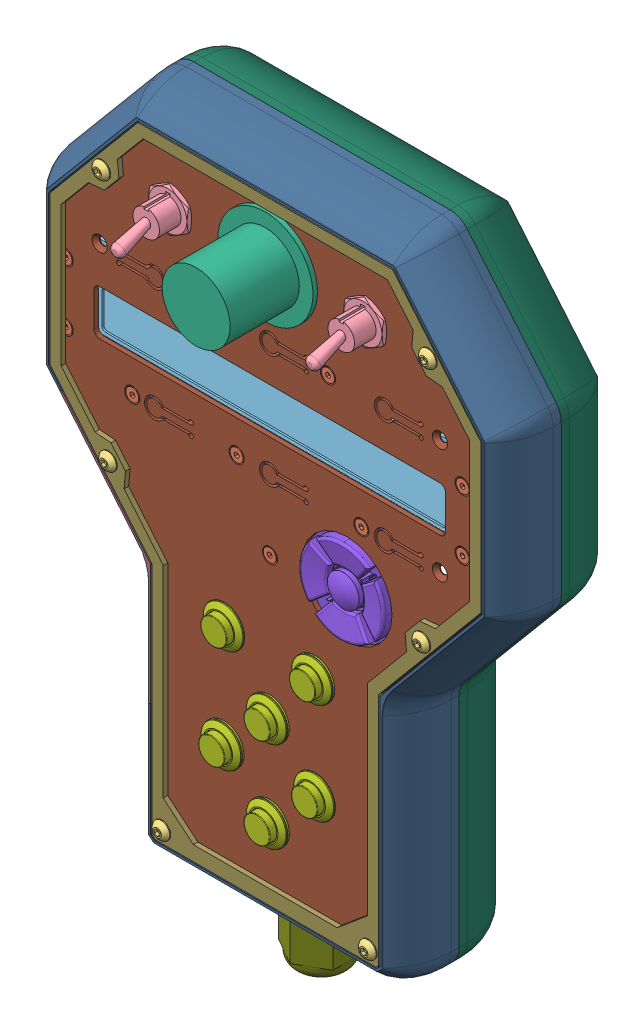
SolidWorks assembly Montagem, configuration Rounded. Lengths in mm.
Overall size (211 315 80.5).
60 component instances, 19 part files, 130 mates.
Components (placement in the parent):
- hex nut style 1 gradeab_din-3: hex nut style 1 gradeab_din [Hexagon Nut ISO 4032 - M4 - W - N] at (-95.2029 -0.5297 -15.05) x (-0.766044 -0.642788 0) z (0 0 1)
- hex nut style 1 gradeab_din-4: hex nut style 1 gradeab_din [Hexagon Nut ISO 4032 - M4 - W - N] at (42.9071 -0.5197 -15.05) x (0.766044 -0.642788 0) z (0 0 1)
- hex nut style 1 gradeab_din-5: hex nut style 1 gradeab_din [Hexagon Nut ISO 4032 - M4 - W - N] at (-69.6429 -49.9305 2.95) x (0.5 0.866025 0) z (0 0 1)
- hex nut style 1 gradeab_din-6: hex nut style 1 gradeab_din [Hexagon Nut ISO 4032 - M4 - W - N] at (33.6932 120.5695 2.95) x (0.766044 0.642788 0) z (0 0 1)
- hex nut style 1 gradeab_din-7: hex nut style 1 gradeab_din [Hexagon Nut ISO 4032 - M4 - W - N] at (17.3571 -99.7712 2.95)
- hex nut style 1 gradeab_din-8: hex nut style 1 gradeab_din [Hexagon Nut ISO 4032 - M4 - W - N] at (-85.979 120.5695 2.95) x (0.766044 -0.642788 0) z (0 0 1)
- hex nut style 1 gradeab_din-9: hex nut style 1 gradeab_din [Hexagon Nut ISO 4032 - M4 - W - N] at (-69.6429 -99.7712 2.95)
- hex nut style 1 gradeab_din-10: hex nut style 1 gradeab_din [Hexagon Nut ISO 4032 - M4 - W - N] at (45.8324 109.2141 -7.45) x (0.939693 -0.34202 0) z (0 0 -1)
- hex nut style 1 gradeab_din-11: hex nut style 1 gradeab_din [Hexagon Nut ISO 4032 - M4 - W - N] at (-71.6429 -129.7045 -7.45) x (0.5 0.866025 0) z (0 0 -1)
- hex nut style 1 gradeab_din-12: hex nut style 1 gradeab_din [Hexagon Nut ISO 4032 - M4 - W - N] at (19.3571 -129.7045 -7.45) x (1 0 0) z (0 0 -1)
- hex nut style 1 gradeab_din-13: hex nut style 1 gradeab_din [Hexagon Nut ISO 4032 - M4 - W - N] at (-98.1182 109.2141 -7.45) x (-0.939693 -0.34202 0) z (0 0 -1)
- socket countersunk head screw_din-8: socket countersunk head screw_din [DIN 7991 - M3 x 16 --- 12.8C] at (58.8311 39.2309 11.75) x (0 0 -1) z (1 0 0)
- socket countersunk head screw_din-9: socket countersunk head screw_din [DIN 7991 - M3 x 16 --- 12.8C] at (-86.7826 27.8805 11.75) x (0 0 -1) z (-0.923728 -0.383049 0)
- socket countersunk head screw_din-10: socket countersunk head screw_din [DIN 7991 - M3 x 16 --- 12.8C] at (-116.1689 65.7309 11.75) x (0 0 -1) z (-0.923728 -0.383049 0)
- socket countersunk head screw_din-11: socket countersunk head screw_din [DIN 7991 - M3 x 16 --- 12.8C] at (-0.483 78.4595 11.75) x (0 0 -1) z (0.923728 0.383049 0)
- socket countersunk head screw_din-12: socket countersunk head screw_din [DIN 7991 - M3 x 16 --- 12.8C] at (-116.1689 39.2309 11.75) x (0 0 -1) z (-0.923728 -0.383049 0)
- socket countersunk head screw_din-13: socket countersunk head screw_din [DIN 7991 - M3 x 16 --- 12.8C] at (-52.483 78.4595 11.75) x (0 0 -1) z (0.923728 0.383049 0)
- socket countersunk head screw_din-14: socket countersunk head screw_din [DIN 7991 - M3 x 16 --- 12.8C] at (58.8311 65.7309 11.75) x (0 0 -1) z (0.923728 0.383049 0)
- socket countersunk head screw_din-15: socket countersunk head screw_din [DIN 7991 - M3 x 16 --- 12.8C] at (14.2174 27.8805 11.75) x (0 0 -1) z (1 0 0)
- socket countersunk head screw_din-16: socket countersunk head screw_din [DIN 7991 - M3 x 16 --- 12.8C] at (-40.7826 27.8805 11.75) x (0 0 -1) z (0.277326 0.960776 0)
- socket countersunk head screw_din-17: socket countersunk head screw_din [DIN 7991 - M3 x 16 --- 12.8C] at (-26.2001 -3.0051 11.75) x (0 0 -1) z (-0.006263 -0.99998 0)
- hex nut style 1 gradeab_din-15: hex nut style 1 gradeab_din [Hexagon Nut ISO 4032 - M3 - W - N] at (-40.7826 27.8805 0.1586) x (0.012479 -0.999922 0) z (0 0 -1)
- hex nut style 1 gradeab_din-16: hex nut style 1 gradeab_din [Hexagon Nut ISO 4032 - M3 - W - N] at (-52.483 78.4595 0.1586) x (0.904381 -0.426726 0) z (0 0 -1)
- hex nut style 1 gradeab_din-17: hex nut style 1 gradeab_din [Hexagon Nut ISO 4032 - M3 - W - N] at (-0.483 78.4595 0.1586) x (-0.993944 0.109886 0) z (0 0 -1)
- hex nut style 1 gradeab_din-18: hex nut style 1 gradeab_din [Hexagon Nut ISO 4032 - M3 - W - N] at (14.2174 27.8805 0.1586) x (-0.816279 -0.577658 0) z (0 0 -1)
- hex nut style 1 gradeab_din-19: hex nut style 1 gradeab_din [Hexagon Nut ISO 4032 - M3 - W - N] at (-86.7826 27.8805 0.1586) x (-0.525463 -0.850817 0) z (0 0 -1)
- hex nut style 1 gradeab_din-20: hex nut style 1 gradeab_din [Hexagon Nut ISO 4032 - M3 - W - N] at (-116.1689 65.7309 -3.318) x (0.297598 -0.954691 0) z (0 0 -1)
- hex nut style 1 gradeab_din-21: hex nut style 1 gradeab_din [Hexagon Nut ISO 4032 - M3 - W - N] at (-116.1689 39.2309 -3.318) x (0.646896 0.762578 0) z (0 0 -1)
- hex nut style 1 gradeab_din-22: hex nut style 1 gradeab_din [Hexagon Nut ISO 4032 - M3 - W - N] at (58.8311 65.7309 -3.318) x (0.923728 0.383049 0) z (0 0 -1)
- hex nut style 1 gradeab_din-23: hex nut style 1 gradeab_din [Hexagon Nut ISO 4032 - M3 - W - N] at (58.8311 39.2309 -3.318) x (0.923728 0.383049 0) z (0 0 -1)
- hex nut style 1 gradeab_din-24: hex nut style 1 gradeab_din [Hexagon Nut ISO 4032 - M3 - W - N] at (-26.2001 -3.0051 0.1586) x (0.05846 -0.99829 0) z (0 0 -1)
- socket button head screw_iso-9: socket button head screw_iso [ISO 7380 - M4 x 16 --- 16N] at (45.8295 109.2085 15.95) x (0 0 -1) z (1 0 0)
- socket button head screw_iso-10: socket button head screw_iso [ISO 7380 - M4 x 16 --- 16N] at (-98.1153 109.2085 15.95) x (0 0 -1) z (0.767389 -0.641182 0)
- socket button head screw_iso-11: socket button head screw_iso [ISO 7380 - M4 x 16 --- 16N] at (-71.6429 -129.7005 15.95) x (0 0 -1) z (1 0 0)
- socket button head screw_iso-12: socket button head screw_iso [ISO 7380 - M4 x 16 --- 16N] at (19.3571 -129.7005 15.95) x (0 0 -1) z (1 0 0)
- socket button head screw_iso-14: socket button head screw_iso [ISO 7380 - M4 x 16 --- 16N] at (-95.1957 -0.5218 15.95) x (0 0 -1) z (1 0 0)
- socket button head screw_iso-13: socket button head screw_iso [ISO 7380 - M4 x 16 --- 16N] at (42.9099 -0.5218 15.95) x (0 0 -1) z (1 0 0)
- BCV3 112 103 - Controle chave geral-1: BCV3 112 103 - Controle chave geral [Default] at (-69.1429 108.0695 2.25)
- BCV3 112 103 - Controle chave geral-2: BCV3 112 103 - Controle chave geral [Default] at (16.8571 108.0695 2.25)
- LCD Display 4002-1: LCD Display 4002 [Valor predeterminado] at (-28.6689 52.4809 -3.8644)
- Botão emergencia-1: Botão emergencia [Valor predeterminado] at (-26.1429 108.0695 -28.25) x (0.351629 -0.93614 0) z (-0.93614 -0.351629 0)
- AV16HA-1: AV16HA [Valor predeterminado] at (-26.1429 -104.9305 -2.3) x (-0.899754 -0.436397 0) z (-0.436397 0.899754 0)
- AV16HA-2: AV16HA [Valor predeterminado] at (-46.1429 -39.9305 -3.25) x (0.225316 -0.974286 0) z (-0.974286 -0.225316 0)
- AV16HA-3: AV16HA [Valor predeterminado] at (-26.1429 -64.9305 -2.3) x (0.278036 0.960571 0) z (0.960571 -0.278036 0)
- AV16HA-4: AV16HA [Valor predeterminado] at (-6.1429 -84.9305 -3.25) x (0.980248 0.197772 0) z (0.197772 -0.980248 0)
- AV16HA-5: AV16HA [Valor predeterminado] at (-46.1429 -84.9305 -2.3) x (0.999797 0.02015 0) z (0.02015 -0.999797 0)
- AV16HA-6: AV16HA [Valor predeterminado] at (-6.1429 -39.9305 -2.3) x (-0.950101 -0.311942 0) z (-0.311942 0.950101 0)
- PCB-2: PCB [Valor predeterminado] at (-91.4326 8.3805 4.15)
- Teclas_Superiores-2: Teclas_Superiores [Valor predeterminado] at (-91.433 46.0455 4.15)
- TEC001 - Moldura -1: TEC001 - Moldura  [Valor predeterminado] at (-26.1429 -144.6278 -11.25)
- TEC002 - Placa Superior-1: TEC002 - Placa Superior [Valor predeterminado] at (-25.2999 1.2599 9.75)
- TEC003 - Moldura alumínio-1: TEC003 - Moldura alumínio [Valor predeterminado] at (-26.4426 -0.0902 11.75)
- TEC004 - Moldura Borracha-1: TEC004 - Moldura Borracha [Valor predeterminado] at (-26.6429 -144.6278 -11.25)
- TEC005 - Moldura Borracha Inferior-1: TEC005 - Moldura Borracha Inferior [Valor predeterminado] at (-26.6429 -144.6278 -11.25)
- TEC006 - Placa Inferior-1: TEC006 - Placa Inferior [Valor predeterminado] at (-25.2999 1.2599 -34.75) (hidden)
- TEC007 - Moldura  Inferior-1: TEC007 - Moldura  Inferior [Valor predeterminado] at (-26.1429 -144.6278 -11.25)
- Prensa cabo-1: Prensa cabo [Valor predeterminado] at (-26.1429 -154.9305 -11.0191) x (0.5 0 0.866025) z (0 -1 0)
- TEC008 - Pino-1: TEC008 - Pino [Valor predeterminado] at (-127.6429 32.3003 0.75) x (0.794362 -0.607445 0) z (0.607445 0.794362 0)
- TEC008 - Pino-2: TEC008 - Pino [Valor predeterminado] at (-80.1429 -114.1997 -24.25) x (0.610836 -0.791757 0) z (-0.791757 -0.610836 0)
- placa inferior-1: placa inferior [Valor predeterminado] at (-18.5596 4.7575 -324.8091) x (-1 0 0) z (0 0 -1) (hidden)
Mates (geometry in assembly coordinates):
- Coincidente2: coincident: plane of TEC001 - Moldura -1 through (-26.1429 -144.6278 13.75) normal (0 0 1); plane of Botão emergencia-1 through (-33.5271 127.7285 13.75) normal (0 0 1)
- Coincidente24: coincident: plane of TEC001 - Moldura -1 through (-26.1429 -144.6278 9.75) normal (0 0 1); plane of TEC002 - Placa Superior-1 through (-25.2999 1.2599 9.75) normal (0 0 -1)
- Coincidente35: coincident: plane of TEC001 - Moldura -1 through (-49.8107 -84.1997 -11.25) normal (0 1 0); plane of TEC004 - Moldura Borracha-1 through (-50.3107 -84.1997 -11.25) normal (0 -1 0)
- Coincidente36: coincident: plane of TEC002 - Placa Superior-1 through (-25.2999 1.2599 9.75) normal (0 0 -1); plane of TEC004 - Moldura Borracha-1 through (-26.6429 -144.6278 9.75) normal (0 0 1)
- Concêntrico6: concentric: cylinder of AV16HA-1 through (-26.1429 -104.9305 -2.3) axis (0 0 1) radius 7.95; cylinder of TEC002 - Placa Superior-1 through (-26.1429 -104.9305 9.749) axis (0 0 1) radius 8
- Tangente1: tangent: plane of TEC002 - Placa Superior-1 through (-25.2999 1.2599 11.75) normal (0 0 1); face of AV16HA-1
- Concêntrico9: concentric: cylinder of AV16HA-4 through (-6.1429 -84.9305 -3.25) axis (0 0 1) radius 7.95; cylinder of TEC002 - Placa Superior-1 through (-6.1429 -84.9305 9.749) axis (0 0 1) radius 8
- Concêntrico10: concentric: cylinder of AV16HA-3 through (-26.1429 -64.9305 -2.3) axis (0 0 1) radius 7.95; cylinder of TEC002 - Placa Superior-1 through (-26.1429 -64.9305 9.749) axis (0 0 1) radius 8
- Tangente2: tangent: plane of TEC002 - Placa Superior-1 through (-25.2999 1.2599 11.75) normal (0 0 1); face of AV16HA-5
- Tangente3: tangent: plane of TEC002 - Placa Superior-1 through (-25.2999 1.2599 11.75) normal (0 0 1); face of AV16HA-6
- Tangente4: tangent: plane of TEC002 - Placa Superior-1 through (-25.2999 1.2599 11.75) normal (0 0 1); face of AV16HA-4
- Tangente5: tangent: plane of TEC002 - Placa Superior-1 through (-25.2999 1.2599 11.75) normal (0 0 1); face of AV16HA-2
- Tangente6: tangent: plane of TEC002 - Placa Superior-1 through (-25.2999 1.2599 11.75) normal (0 0 1); face of AV16HA-3
- Concêntrico12: concentric: cylinder of Botão emergencia-1 through (-26.1429 108.0695 -50.7451) axis (0 0 -1) radius 15; cylinder of TEC002 - Placa Superior-1 through (-26.1429 108.0695 9.749) axis (0 0 1) radius 11.25
- Concêntrico13: concentric: cylinder of BCV3 112 103 - Controle chave geral-1 through (-69.1429 108.0695 23.25) axis (0 0 -1) radius 5.85; cylinder of TEC002 - Placa Superior-1 through (-69.1429 108.0695 9.749) axis (0 0 1) radius 6
- Concêntrico15: concentric: cylinder of BCV3 112 103 - Controle chave geral-2 through (16.8571 108.0695 23.25) axis (0 0 -1) radius 5.85; cylinder of TEC002 - Placa Superior-1 through (16.8571 108.0695 9.749) axis (0 0 1) radius 6
- Coincidente38: coincident: plane of BCV3 112 103 - Controle chave geral-1 through (-69.1429 117.8845 11.75) normal (0 0 -1); plane of TEC002 - Placa Superior-1 through (-25.2999 1.2599 11.75) normal (0 0 1)
- Coincidente39: coincident: plane of BCV3 112 103 - Controle chave geral-2 through (16.8571 117.8845 11.75) normal (0 0 -1); plane of TEC002 - Placa Superior-1 through (-25.2999 1.2599 11.75) normal (0 0 1)
- Coincidente40: coincident: plane of TEC001 - Moldura -1 through (-39.9429 -142.4305 -3.2826) normal (0.5 0 -0.866025); plane of Prensa cabo-1 through (-39.7429 -142.4305 -3.1671) normal (-0.5 0 0.866025)
- Coincidente41: coincident: plane of TEC001 - Moldura -1 through (-26.1429 -142.4305 4.6849) normal (-0.5 0 -0.866025); plane of Prensa cabo-1 through (-26.1429 -142.4305 4.6849) normal (0.5 0 0.866025)
- Coincidente42: coincident: plane of TEC001 - Moldura -1 through (-26.1429 -142.4305 -11.25) normal (0 1 0); plane of Prensa cabo-1 through (-26.1429 -142.4305 -11.0191) normal (0 -1 0)
- Distância9: distance = 0.5 mm: plane of TEC002 - Placa Superior-1 through (-121.1429 88.7866 11.75) normal (-1 0 0); plane of TEC001 - Moldura -1 through (-121.6429 88.9571 9.75) normal (1 0 0)
- Distância10: distance = 0.5 mm: plane of TEC002 - Placa Superior-1 through (30.0211 135.0695 11.75) normal (0 1 0); plane of TEC001 - Moldura -1 through (30.2446 135.5695 9.75) normal (0 -1 0)
- Coincidente49: coincident: plane of TEC002 - Placa Superior-1 through (-25.2999 1.2599 11.75) normal (0 0 1); plane of TEC003 - Moldura alumínio-1 through (-26.4426 -0.0902 11.75) normal (0 0 -1)
- Coincidente50: coincident: plane of TEC002 - Placa Superior-1 through (-121.1429 88.7866 11.75) normal (-1 0 0); plane of TEC003 - Moldura alumínio-1 through (-121.1429 88.7866 13.75) normal (-1 0 0)
- Coincidente51: coincident: plane of TEC002 - Placa Superior-1 through (-74.8228 -134.9305 11.75) normal (0 -1 0); plane of TEC003 - Moldura alumínio-1 through (-74.8228 -134.9305 13.75) normal (0 -1 0)
- Coincidente52: coincident: plane of TEC001 - Moldura -1 through (-86.6429 -144.6278 13.75) normal (-1 0 0); plane of TEC004 - Moldura Borracha-1 through (-86.6429 -144.6278 13.75) normal (-1 0 0)
- Coincidente53: coincident: plane of TEC001 - Moldura -1 through (-26.1429 145.5695 13.75) normal (0 1 0); plane of TEC007 - Moldura  Inferior-1 through (-26.1429 145.5695 13.75) normal (0 1 0)
- Coincidente54: coincident: plane of TEC001 - Moldura -1 through (-204.8631 5.3363 13.75) normal (-0.766044 0.642788 0); plane of TEC007 - Moldura  Inferior-1 through (-204.8631 5.3363 13.75) normal (-0.766044 0.642788 0)
- Coincidente55: coincident: plane of TEC001 - Moldura -1 through (152.5774 5.3363 13.75) normal (0.766044 0.642788 0); plane of TEC007 - Moldura  Inferior-1 through (152.5774 5.3363 13.75) normal (0.766044 0.642788 0)
- Coincidente56: coincident: plane of TEC006 - Placa Inferior-1 through (-25.2999 1.2599 -33.25) normal (0 0 1); plane of TEC007 - Moldura  Inferior-1 through (-26.1429 -144.6278 -33.25) normal (0 0 -1)
- Distância11: distance = 0.5 mm: plane of TEC006 - Placa Inferior-1 through (30.0211 135.0695 -33.25) normal (0 1 0); plane of TEC007 - Moldura  Inferior-1 through (30.2446 135.5695 -33.25) normal (0 -1 0)
- Distância12: distance = 0.5 mm: plane of TEC006 - Placa Inferior-1 through (-121.1429 88.7866 -33.25) normal (-1 0 0); plane of TEC007 - Moldura  Inferior-1 through (-121.6429 88.9571 -33.25) normal (1 0 0)
- Coincidente57: coincident: plane of TEC007 - Moldura  Inferior-1 through (-26.1429 -144.6278 -11.25) normal (0 0 1); plane of TEC005 - Moldura Borracha Inferior-1 through (-26.6429 -144.6278 -11.25) normal (0 0 1)
- Coincidente58: coincident: plane of TEC007 - Moldura  Inferior-1 through (-49.8107 -84.1997 -11.25) normal (0 1 0); plane of TEC005 - Moldura Borracha Inferior-1 through (-50.3107 -84.1997 -11.25) normal (0 -1 0)
- Coincidente59: coincident: plane of TEC007 - Moldura  Inferior-1 through (-7.3536 -128.8618 13.75) normal (-0.766044 -0.642788 0); plane of TEC005 - Moldura Borracha Inferior-1 through (-7.5602 -128.6156 13.75) normal (-0.766044 -0.642788 0)
- Paralelo2: parallel: plane of TEC001 - Moldura -1 through (30.2446 135.5695 9.75) normal (0 -1 0); plane of BCV3 112 103 - Controle chave geral-1 through (-77.1429 122.5695 10.25) normal (0 1 0)
- Paralelo3: parallel: plane of TEC001 - Moldura -1 through (30.2446 135.5695 9.75) normal (0 -1 0); plane of BCV3 112 103 - Controle chave geral-2 through (8.8571 122.5695 10.25) normal (0 1 0)
- Concêntrico17: concentric: cylinder of TEC001 - Moldura -1 through (33.6932 120.5695 -11.25) axis (0 0 1) radius 2.2; cylinder of hex nut style 1 gradeab_din-6 through (33.6932 120.5695 -0.25) axis (0 0 1) radius 1.65
- Concêntrico18: concentric: cylinder of TEC001 - Moldura -1 through (-85.979 120.5695 -11.25) axis (0 0 1) radius 2.2; cylinder of hex nut style 1 gradeab_din-8 through (-85.979 120.5695 -0.25) axis (0 0 1) radius 1.65
- Paralelo4: parallel: plane of TEC001 - Moldura -1 through (-90.1865 121.3114 -0.25) normal (0.939693 0.34202 0); plane of hex nut style 1 gradeab_din-8 through (-89.9591 121.2713 -0.25) normal (-0.939693 -0.34202 0)
- Paralelo5: parallel: plane of TEC001 - Moldura -1 through (-87.4403 124.5843 -0.25) normal (0.766044 -0.642788 0); plane of hex nut style 1 gradeab_din-8 through (-87.3613 124.3672 -0.25) normal (-0.766044 0.642788 0)
- Coincidente67: coincident: plane of TEC001 - Moldura -1 through (-26.1429 -144.6278 -0.25) normal (0 0 1); plane of hex nut style 1 gradeab_din-8 through (-83.3812 123.6655 -0.25) normal (0 0 -1)
- Paralelo6: parallel: plane of TEC001 - Moldura -1 through (30.947 123.8424 -0.25) normal (0.939693 -0.34202 0); plane of hex nut style 1 gradeab_din-6 through (31.0955 123.6655 -0.25) normal (-0.939693 0.34202 0)
- Coincidente69: coincident: plane of TEC001 - Moldura -1 through (-26.1429 -144.6278 -0.25) normal (0 0 1); plane of hex nut style 1 gradeab_din-6 through (31.0955 123.6655 -0.25) normal (0 0 -1)
- Concêntrico21: concentric: cylinder of TEC004 - Moldura Borracha-1 through (-69.6429 -49.9305 -11.25) axis (0 0 1) radius 2.2; cylinder of hex nut style 1 gradeab_din-5 through (-69.6429 -49.9305 -0.25) axis (0 0 1) radius 1.65
- Paralelo9: parallel: plane of TEC004 - Moldura Borracha-1 through (-65.9429 -52.0667 -0.25) normal (-1 0 0); plane of hex nut style 1 gradeab_din-5 through (-73.1429 -47.9097 -0.25) normal (-1 0 0)
- Coincidente76: coincident: plane of TEC004 - Moldura Borracha-1 through (-26.6429 -144.6278 -0.25) normal (0 0 1); plane of hex nut style 1 gradeab_din-5 through (-73.1429 -47.9097 -0.25) normal (0 0 -1)
- Concêntrico22: concentric: cylinder of TEC001 - Moldura -1 through (17.3571 -99.7712 -11.25) axis (0 0 1) radius 2.2; cylinder of hex nut style 1 gradeab_din-7 through (17.3571 -99.7712 -0.25) axis (0 0 1) radius 1.65
- Paralelo10: parallel: plane of TEC001 - Moldura -1 through (21.0571 -101.9074 -0.25) normal (-1 0 0); plane of hex nut style 1 gradeab_din-7 through (13.8571 -97.7505 -0.25) normal (-1 0 0)
- Coincidente78: coincident: plane of TEC001 - Moldura -1 through (-26.1429 -144.6278 -0.25) normal (0 0 1); plane of hex nut style 1 gradeab_din-7 through (17.3571 -95.7298 -0.25) normal (0 0 -1)
- Concêntrico23: concentric: cylinder of TEC001 - Moldura -1 through (-69.6429 -99.7712 -11.25) axis (0 0 1) radius 2.2; cylinder of hex nut style 1 gradeab_din-9 through (-69.6429 -99.7712 -0.25) axis (0 0 1) radius 1.65
- Paralelo11: parallel: plane of TEC001 - Moldura -1 through (-65.9429 -101.9074 -0.25) normal (-1 0 0); plane of hex nut style 1 gradeab_din-9 through (-73.1429 -97.7505 -0.25) normal (-1 0 0)
- Coincidente80: coincident: plane of TEC001 - Moldura -1 through (-26.1429 -144.6278 -0.25) normal (0 0 1); plane of hex nut style 1 gradeab_din-9 through (-69.6429 -95.7298 -0.25) normal (0 0 -1)
- Concêntrico24: concentric: cylinder of TEC001 - Moldura -1 through (-71.6429 -129.7045 -11.25) axis (0 0 1) radius 2.2; cylinder of hex nut style 1 gradeab_din-11 through (-71.6429 -129.7045 -4.25) axis (0 0 -1) radius 1.65
- Paralelo12: parallel: plane of TEC001 - Moldura -1 through (-67.9429 -127.5683 3.75) normal (-0.5 -0.866025 0); plane of hex nut style 1 gradeab_din-11 through (-68.1429 -127.6838 -4.25) normal (0.5 0.866025 0)
- Concêntrico25: concentric: cylinder of TEC001 - Moldura -1 through (19.3571 -129.7045 -11.25) axis (0 0 1) radius 2.2; cylinder of hex nut style 1 gradeab_din-12 through (19.3571 -129.7045 -4.25) axis (0 0 -1) radius 1.65
- Paralelo13: parallel: plane of TEC001 - Moldura -1 through (15.6571 -131.8407 3.75) normal (1 0 0); plane of hex nut style 1 gradeab_din-12 through (22.8571 -131.7252 -4.25) normal (1 0 0)
- Concêntrico27: concentric: cylinder of TEC001 - Moldura -1 through (45.8324 109.2141 -11.25) axis (0 0 1) radius 2.2; cylinder of hex nut style 1 gradeab_din-10 through (45.8324 109.2141 -4.25) axis (0 0 -1) radius 1.65
- Paralelo14: parallel: plane of TEC001 - Moldura -1 through (43.0861 112.487 3.75) normal (0.173648 -0.984808 0); plane of hex nut style 1 gradeab_din-10 through (48.4302 106.1182 -4.25) normal (0.173648 -0.984808 0)
- Concêntrico28: concentric: cylinder of TEC001 - Moldura -1 through (-98.1182 109.2141 -11.25) axis (0 0 1) radius 2.2; cylinder of hex nut style 1 gradeab_din-13 through (-98.1182 109.2141 -4.25) axis (0 0 -1) radius 1.65
- Paralelo15: parallel: plane of TEC001 - Moldura -1 through (-99.5794 113.2289 3.75) normal (-0.173648 -0.984808 0); plane of hex nut style 1 gradeab_din-13 through (-96.7359 105.4164 -4.25) normal (-0.173648 -0.984808 0)
- Coincidente89: coincident: plane of TEC001 - Moldura -1 through (-26.1429 -144.6278 -11.25) normal (0 0 -1); plane of TEC007 - Moldura  Inferior-1 through (-26.1429 -144.6278 -11.25) normal (0 0 1)
- Concêntrico53: concentric: cone of TEC002 - Placa Superior-1 through (14.2174 27.8805 11.75) axis (0 0 -1); cylinder of socket countersunk head screw_din-15 through (14.2174 27.8805 11.75) axis (0 0 1) radius 1.5
- Concêntrico54: concentric: cone of TEC002 - Placa Superior-1 through (58.8311 39.2309 11.75) axis (0 0 -1); cylinder of socket countersunk head screw_din-8 through (58.8311 39.2309 11.75) axis (0 0 1) radius 1.5
- Concêntrico55: concentric: cone of TEC002 - Placa Superior-1 through (58.8311 65.7309 11.75) axis (0 0 -1); cylinder of socket countersunk head screw_din-14 through (58.8311 65.7309 11.75) axis (0 0 1) radius 1.5
- Concêntrico56: concentric: cone of TEC002 - Placa Superior-1 through (-0.483 78.4595 11.75) axis (0 0 -1); cylinder of socket countersunk head screw_din-11 through (-0.483 78.4595 11.75) axis (0 0 1) radius 1.5
- Concêntrico57: concentric: cone of TEC002 - Placa Superior-1 through (-52.483 78.4595 11.75) axis (0 0 -1); cylinder of socket countersunk head screw_din-13 through (-52.483 78.4595 11.75) axis (0 0 1) radius 1.5
- Concêntrico58: concentric: circle of TEC002 - Placa Superior-1; cylinder of socket countersunk head screw_din-10 through (-116.1689 65.7309 11.75) axis (0 0 1) radius 1.5
- Concêntrico59: concentric: cylinder of socket countersunk head screw_din-12 through (-116.1689 39.2309 11.75) axis (0 0 1) radius 1.5; circle of TEC002 - Placa Superior-1
- Concêntrico60: concentric: cone of TEC002 - Placa Superior-1 through (-86.7826 27.8805 11.75) axis (0 0 -1); cylinder of socket countersunk head screw_din-9 through (-86.7826 27.8805 11.75) axis (0 0 1) radius 1.5
- Coincidente105: coincident: plane of TEC002 - Placa Superior-1 through (-25.2999 1.2599 11.75) normal (0 0 1); plane of socket countersunk head screw_din-15 through (14.2174 27.8805 11.75) normal (0 0 1)
- Coincidente106: coincident: plane of TEC002 - Placa Superior-1 through (-25.2999 1.2599 11.75) normal (0 0 1); plane of socket countersunk head screw_din-8 through (58.8311 39.2309 11.75) normal (0 0 1)
- Coincidente107: coincident: plane of TEC002 - Placa Superior-1 through (-25.2999 1.2599 11.75) normal (0 0 1); line of socket countersunk head screw_din-14 through (58.1215 64.8054 11.75) axis (-0.383049 0.923728 0)
- Coincidente108: coincident: plane of TEC002 - Placa Superior-1 through (-25.2999 1.2599 11.75) normal (0 0 1); plane of socket countersunk head screw_din-11 through (-0.483 78.4595 11.75) normal (0 0 1)
- Coincidente109: coincident: plane of TEC002 - Placa Superior-1 through (-25.2999 1.2599 11.75) normal (0 0 1); plane of socket countersunk head screw_din-10 through (-116.1689 65.7309 11.75) normal (0 0 1)
- Coincidente110: coincident: plane of TEC002 - Placa Superior-1 through (-25.2999 1.2599 11.75) normal (0 0 1); circle of socket countersunk head screw_din-13
- Coincidente111: coincident: plane of TEC002 - Placa Superior-1 through (-25.2999 1.2599 11.75) normal (0 0 1); plane of socket countersunk head screw_din-9 through (-86.7826 27.8805 11.75) normal (0 0 1)
- Coincidente112: coincident: plane of TEC002 - Placa Superior-1 through (-25.2999 1.2599 11.75) normal (0 0 1); plane of socket countersunk head screw_din-12 through (-116.1689 39.2309 11.75) normal (0 0 1)
- Concêntrico61: concentric: cone of TEC002 - Placa Superior-1 through (-40.7826 27.8805 11.75) axis (0 0 -1); cylinder of socket countersunk head screw_din-16 through (-40.7826 27.8805 11.75) axis (0 0 1) radius 1.5
- Coincidente113: coincident: plane of TEC002 - Placa Superior-1 through (-25.2999 1.2599 11.75) normal (0 0 1); plane of socket countersunk head screw_din-16 through (-40.7826 27.8805 11.75) normal (0 0 1)
- Coincidente114: coincident: plane of TEC002 - Placa Superior-1 through (-25.2999 1.2599 11.75) normal (0 0 1); plane of socket countersunk head screw_din-17 through (-26.2001 -3.0051 11.75) normal (0 0 1)
- Concêntrico63: concentric: cone of socket countersunk head screw_din-13 through (-52.483 78.4595 -4.25) axis (0 0 -1); cylinder of hex nut style 1 gradeab_din-16 through (-52.483 78.4595 25.1961) axis (0 0 -1) radius 1.5
- Concêntrico64: concentric: cylinder of socket countersunk head screw_din-11 through (-0.483 78.4595 11.75) axis (0 0 1) radius 1.5; cylinder of hex nut style 1 gradeab_din-17 through (-0.483 78.4595 25.1961) axis (0 0 -1) radius 1.5
- Concêntrico65: concentric: cylinder of socket countersunk head screw_din-15 through (14.2174 27.8805 11.75) axis (0 0 1) radius 1.5; cylinder of hex nut style 1 gradeab_din-18 through (14.2174 27.8805 25.1961) axis (0 0 -1) radius 1.5
- Concêntrico66: concentric: cylinder of socket countersunk head screw_din-9 through (-86.7826 27.8805 11.75) axis (0 0 1) radius 1.5; cylinder of hex nut style 1 gradeab_din-19 through (-86.7826 27.8805 25.1961) axis (0 0 -1) radius 1.5
- Concêntrico67: concentric: cylinder of socket countersunk head screw_din-10 through (-116.1689 65.7309 11.75) axis (0 0 1) radius 1.5; cylinder of hex nut style 1 gradeab_din-20 through (-116.1689 65.7309 21.7195) axis (0 0 -1) radius 1.5
- Concêntrico68: concentric: cylinder of socket countersunk head screw_din-12 through (-116.1689 39.2309 11.75) axis (0 0 1) radius 1.5; cylinder of hex nut style 1 gradeab_din-21 through (-116.1689 39.2309 21.7195) axis (0 0 -1) radius 1.5
- Concêntrico69: concentric: cylinder of socket countersunk head screw_din-14 through (58.8311 65.7309 11.75) axis (0 0 1) radius 1.5; cylinder of hex nut style 1 gradeab_din-22 through (58.8311 65.7309 21.7195) axis (0 0 -1) radius 1.5
- Concêntrico70: concentric: cylinder of socket countersunk head screw_din-8 through (58.8311 39.2309 11.75) axis (0 0 1) radius 1.5; cylinder of hex nut style 1 gradeab_din-23 through (58.8311 39.2309 21.7195) axis (0 0 -1) radius 1.5
- Concêntrico71: concentric: cylinder of socket countersunk head screw_din-17 through (-26.2001 -3.0051 11.75) axis (0 0 1) radius 1.5; cylinder of hex nut style 1 gradeab_din-24 through (-26.2001 -3.0051 2.5586) axis (0 0 -1) radius 1.25
- Concêntrico72: concentric: cylinder of TEC003 - Moldura alumínio-1 through (45.8295 109.2085 11.749) axis (0 0 1) radius 2.1; cylinder of socket button head screw_iso-9 through (45.8295 109.2085 15.95) axis (0 0 1) radius 3.8
- Coincidente124: coincident: plane of TEC003 - Moldura alumínio-1 through (-26.4426 -0.0902 13.75) normal (0 0 1); plane of socket button head screw_iso-9 through (45.8295 111.2085 13.75) normal (0 0 -1)
- Concêntrico73: concentric: cylinder of TEC003 - Moldura alumínio-1 through (-98.1153 109.2085 11.749) axis (0 0 1) radius 2.1; cylinder of socket button head screw_iso-10 through (-98.1153 109.2085 15.95) axis (0 0 1) radius 3.8
- Coincidente125: coincident: plane of TEC003 - Moldura alumínio-1 through (-26.4426 -0.0902 13.75) normal (0 0 1); plane of socket button head screw_iso-10 through (-96.8329 110.7433 13.75) normal (0 0 -1)
- Concêntrico74: concentric: cylinder of TEC003 - Moldura alumínio-1 through (-71.6429 -129.7005 11.749) axis (0 0 1) radius 2.1; cylinder of socket button head screw_iso-11 through (-71.6429 -129.7005 15.95) axis (0 0 1) radius 3.8
- Coincidente126: coincident: plane of TEC003 - Moldura alumínio-1 through (-26.4426 -0.0902 13.75) normal (0 0 1); plane of socket button head screw_iso-11 through (-71.6429 -127.7005 13.75) normal (0 0 -1)
- Concêntrico75: concentric: cylinder of TEC003 - Moldura alumínio-1 through (19.3571 -129.7005 11.749) axis (0 0 1) radius 2.1; cylinder of socket button head screw_iso-12 through (19.3571 -129.7005 15.95) axis (0 0 1) radius 3.8
- Coincidente127: coincident: plane of TEC003 - Moldura alumínio-1 through (-26.4426 -0.0902 13.75) normal (0 0 1); plane of socket button head screw_iso-12 through (19.3571 -127.7005 13.75) normal (0 0 -1)
- Concêntrico76: concentric: cylinder of socket countersunk head screw_din-16 through (-40.7826 27.8805 11.75) axis (0 0 1) radius 1.5; cylinder of hex nut style 1 gradeab_din-15 through (-40.7826 27.8805 2.5586) axis (0 0 -1) radius 1.25
- Concêntrico77: concentric: cylinder of TEC007 - Moldura  Inferior-1 through (-127.6429 32.3003 -24.25) axis (0 0 1) radius 2.2; cylinder of TEC008 - Pino-1 through (-127.6429 32.3003 -24.25) axis (0 0 1) radius 2
- Coincidente138: coincident: plane of TEC007 - Moldura  Inferior-1 through (-127.6429 32.3003 -24.25) normal (0 0 1); plane of TEC008 - Pino-1 through (-127.6429 32.3003 -24.25) normal (0 0 -1)
- Concêntrico78: concentric: cylinder of TEC007 - Moldura  Inferior-1 through (-80.1429 -114.1997 -24.25) axis (0 0 1) radius 2.2; cylinder of TEC008 - Pino-2 through (-80.1429 -114.1997 0.75) axis (0 0 -1) radius 2
- Coincidente139: coincident: plane of TEC007 - Moldura  Inferior-1 through (-80.1429 -114.1997 -24.25) normal (0 0 1); plane of TEC008 - Pino-2 through (-80.1429 -114.1997 -24.25) normal (0 0 -1)
- Coincidente140: coincident: plane of TEC003 - Moldura alumínio-1 through (-26.4426 -0.0902 13.75) normal (0 0 1); plane of socket button head screw_iso-14 through (-95.1957 1.4782 13.75) normal (0 0 -1)
- Concêntrico80: concentric: cylinder of TEC003 - Moldura alumínio-1 through (-95.1957 -0.5218 11.749) axis (0 0 1) radius 2.1; cylinder of socket button head screw_iso-14 through (-95.1957 -0.5218 15.95) axis (0 0 1) radius 2
- Coincidente141: coincident: plane of TEC003 - Moldura alumínio-1 through (-26.4426 -0.0902 13.75) normal (0 0 1); plane of socket button head screw_iso-13 through (42.9099 1.4782 13.75) normal (0 0 -1)
- Concêntrico82: concentric: cylinder of TEC003 - Moldura alumínio-1 through (42.9099 -0.5218 11.749) axis (0 0 1) radius 2.1; cylinder of socket button head screw_iso-13 through (42.9099 -0.5218 15.95) axis (0 0 1) radius 2
- Concêntrico83: concentric: cylinder of hex nut style 1 gradeab_din-3 through (-95.2029 -0.5297 -18.25) axis (0 0 1) radius 1.65; cylinder of TEC005 - Moldura Borracha Inferior-1 through (-95.2029 -0.5297 -11.249) axis (0 0 -1) radius 2.1
- Paralelo16: parallel: plane of hex nut style 1 gradeab_din-3 through (-96.5852 -4.3274 -18.25) normal (-0.766044 -0.642788 0); plane of TEC005 - Moldura Borracha Inferior-1 through (-90.9954 0.2122 -26.25) normal (-0.766044 -0.642788 0)
- Coincidente143: coincident: plane of hex nut style 1 gradeab_din-3 through (-92.6051 -3.6256 -18.25) normal (0 0 -1); line of TEC005 - Moldura Borracha Inferior-1 through (-93.7417 3.485 -18.25) axis (0.642788 -0.766044 0)
- Concêntrico84: concentric: cylinder of hex nut style 1 gradeab_din-4 through (42.9071 -0.5197 -18.25) axis (0 0 1) radius 1.65; cylinder of TEC007 - Moldura  Inferior-1 through (42.9071 -0.5197 -36.251) axis (0 0 1) radius 2.2
- Paralelo17: parallel: plane of hex nut style 1 gradeab_din-4 through (46.8872 -1.2215 -18.25) normal (0.766044 -0.642788 0); plane of TEC007 - Moldura  Inferior-1 through (41.4459 3.495 -26.25) normal (0.766044 -0.642788 0)
- Coincidente145: coincident: plane of hex nut style 1 gradeab_din-4 through (45.5049 2.5762 -18.25) normal (0 0 -1); line of TEC007 - Moldura  Inferior-1 through (38.6996 0.2222 -18.25) axis (0.642788 0.766044 0)
- Coincidente146: coincident: plane of hex nut style 1 gradeab_din-10 through (44.4501 105.4164 -4.25) normal (0 0 1); line of TEC001 - Moldura -1 through (43.0861 112.487 -4.25) axis (-0.34202 -0.939693 0)
- Coincidente147: coincident: plane of hex nut style 1 gradeab_din-13 through (-99.5004 113.0119 -4.25) normal (0 0 1); line of TEC001 - Moldura -1 through (-99.5794 113.2289 -4.25) axis (-0.642788 -0.766044 0)
- Coincidente148: coincident: plane of hex nut style 1 gradeab_din-12 through (19.3571 -133.7459 -4.25) normal (0 0 1); moEndPointRef_w of TEC001 - Moldura -1
- Coincidente149: coincident: plane of hex nut style 1 gradeab_din-11 through (-68.1429 -131.7252 -4.25) normal (0 0 1); line of TEC001 - Moldura -1 through (-71.6429 -125.4321 -4.25) axis (-0.866025 -0.5 0)
- Distância13: distance = 5.6 mm: plane of PCB-2 through (-64.1256 -24.1545 4.15) normal (0 0 1); plane of TEC002 - Placa Superior-1 through (-25.2999 1.2599 9.75) normal (0 0 -1)
- Concêntrico86: concentric: circle of PCB-2; cylinder of TEC002 - Placa Superior-1 through (7.7564 1.0695 9.749) axis (0 0 1) radius 20
- Paralelo18: parallel: plane of PCB-2 through (38.6944 33.3805 2.5586) normal (1 0 0); plane of TEC002 - Placa Superior-1 through (68.8571 88.7866 11.75) normal (1 0 0)
- Coincidente153: coincident: plane of PCB-2 through (-64.1256 -24.1545 4.15) normal (0 0 1); plane of Teclas_Superiores-2 through (-91.433 71.9185 4.15) normal (0 0 1)
- Coincidente154: coincident: plane of PCB-2 through (-91.5596 8.3805 2.5586) normal (-1 0 0); plane of Teclas_Superiores-2 through (-91.56 72.0455 2.5586) normal (-1 0 0)
- Concêntrico87: concentric: cylinder of AV16HA-5 through (-46.1429 -84.9305 -2.3) axis (0 0 1) radius 7.95; cylinder of TEC002 - Placa Superior-1 through (-46.1429 -84.9305 9.749) axis (0 0 1) radius 8
- Concêntrico88: concentric: cylinder of AV16HA-6 through (-6.1429 -39.9305 -2.3) axis (0 0 1) radius 7.95; cylinder of TEC002 - Placa Superior-1 through (-6.1429 -39.9305 9.749) axis (0 0 1) radius 8
- Concêntrico89: concentric: cylinder of AV16HA-2 through (-46.1429 -39.9305 -3.25) axis (0 0 1) radius 6.25; cylinder of TEC002 - Placa Superior-1 through (-46.1429 -39.9305 9.749) axis (0 0 1) radius 8
- Concêntrico90: concentric: cylinder of Teclas_Superiores-2 through (-26.1329 77.7395 7.958) axis (0 0 -1) radius 1.75; cylinder of TEC002 - Placa Superior-1 through (-26.1329 77.7395 1.75) axis (0 0 1) radius 3.5
- Coincidente156: coincident: plane of PCB-2 through (-91.5596 8.3805 2.5586) normal (-1 0 0); plane of placa inferior-1 through (-91.5596 8.5075 -326.8091) normal (-1 0 0)
- Coincidente157: coincident: plane of PCB-2 through (-91.4326 33.5075 2.5586) normal (0 1 0); plane of placa inferior-1 through (54.4404 33.5075 -326.8091) normal (0 1 0)
- Paralelo19: parallel: plane of PCB-2 through (-64.1256 -24.1545 2.5586) normal (0 0 -1); plane of placa inferior-1 through (-18.5596 4.7575 -326.8091) normal (0 0 -1)
